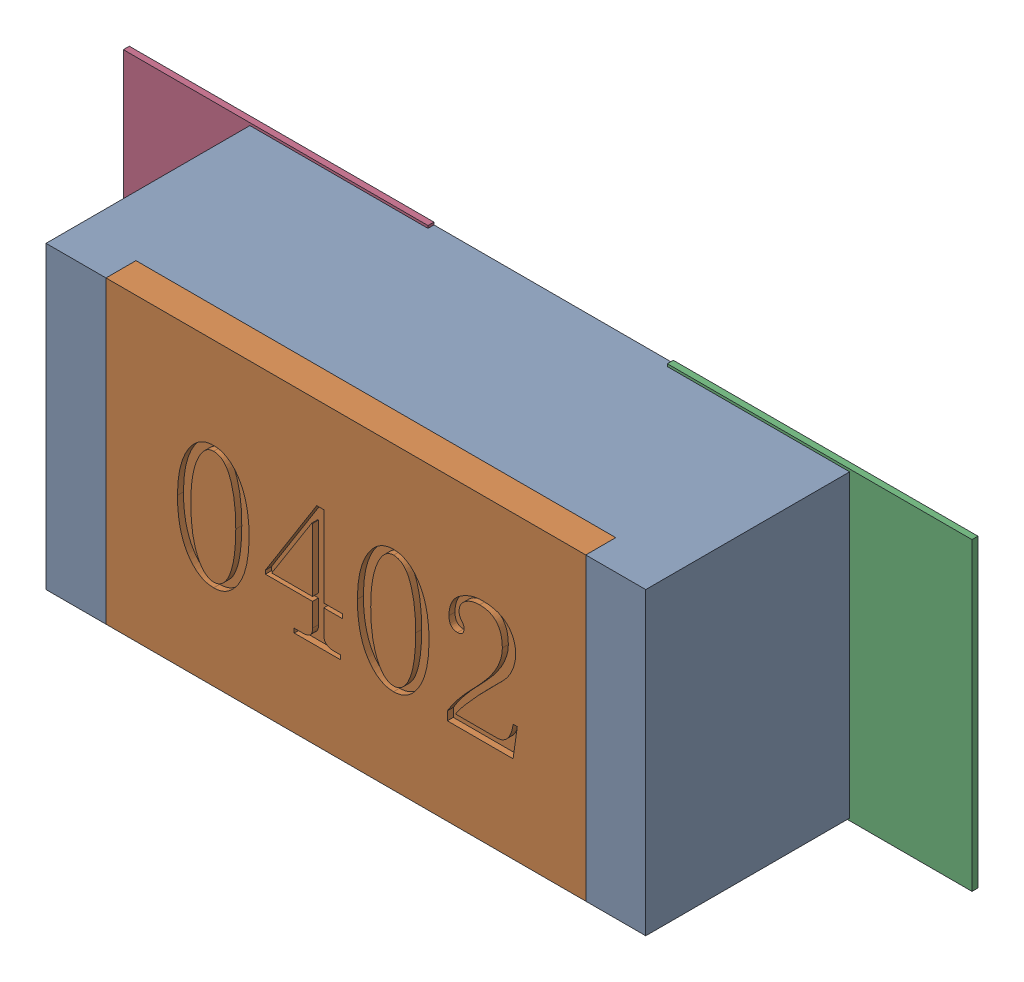
SolidWorks assembly R73, configuration Défaut. Lengths in mm.
Overall size (1.42 0.51 0.35).
5 component instances, 2 part files, 0 mates.
Components (placement in the parent):
- R0402-1: R0402 [Défaut] at (32.1914 -12.5731 0) x (1 0 0) z (0 0 1) size (1 0.5 0.35)
- 6504207776-1: 6504207776 [Défaut] at (32.6414 -12.573 0) size (0.51 0.51 0.01)
  - Extruded-1: Extruded [Défaut] at origin size (0.51 0.51 0.01)
- 6504207776-2: 6504207776 [Défaut] at (31.7343 -12.573 0) size (0.51 0.51 0.01)
  - Extruded-1: Extruded [Défaut] at origin size (0.51 0.51 0.01)
